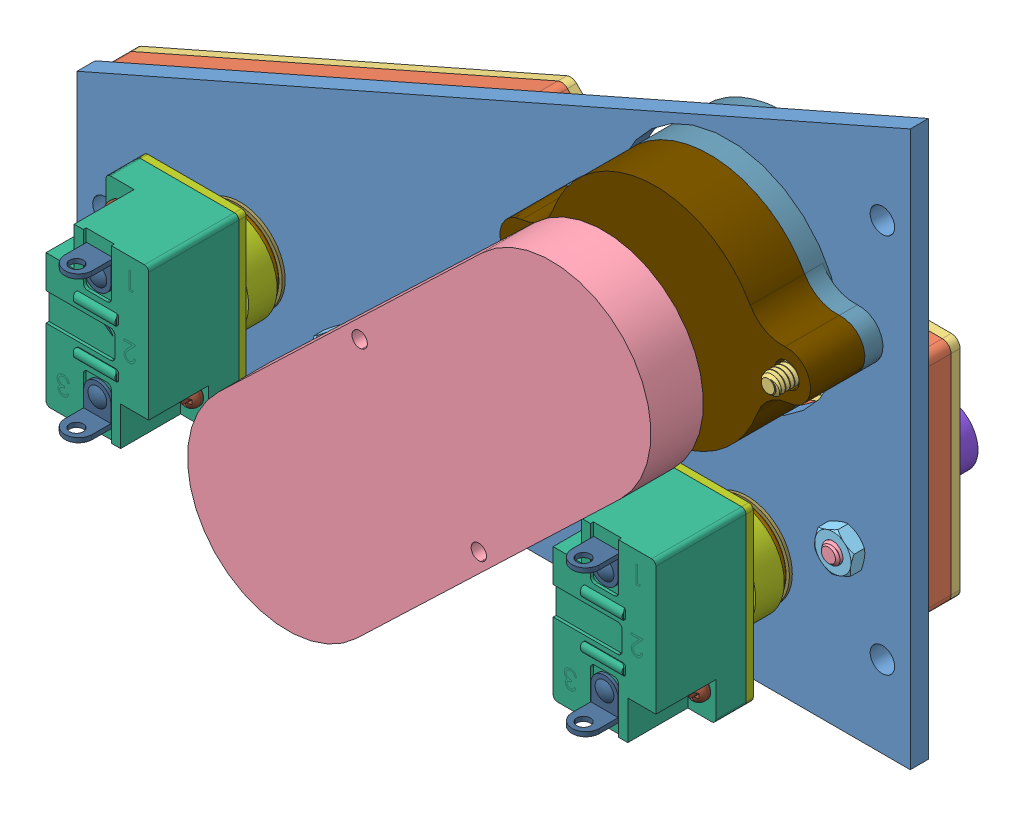
SolidWorks assembly ELEC Panel, configuration Default. Lengths in mm.
Overall size (184.74 131.22 81.65).
84 component instances, 31 part files, 35 mates.
Components (placement in the parent):
- ELEC Panel Backplate-1: ELEC Panel Backplate [Default] at origin size (146.05 97.28 3.4)
- ELEC Panel Lightplate-1: ELEC Panel Lightplate [Default] at (829.3636 5946.9 -37.6062) x (1 0 0) z (0 0 -1) size (144.46 65.08 4.76)
- ELEC Panel Legend Plate-1: ELEC Panel Legend Plate [Default] at (829.3636 5946.9 10.2422) x (1 0 0) z (0 0 -1) size (144.46 65.08 1.59)
- 91249A148 - PHS, 6-32 X .500, 18-8, BLACK-OXIDE-1: 91249A148 - PHS, 6-32 X .500, 18-8, BLACK-OXIDE [91249A148] at (-11.176 28.575 3.175) x (-0.851837 -0.523808 0) z (0 0 -1) size (6.86 6.86 15.21)
- 90760A007 - NUT, 6-32, JAM, STEEL, ZINC-PLATED-1: 90760A007 - NUT, 6-32, JAM, STEEL, ZINC-PLATED [90760A007] at (-11.176 28.575 1.1906) x (0.356702 -0.934218 0) z (-0.934218 -0.356702 0) size (6.35 2.99 7.33)
- 91249A148 - PHS, 6-32 X .500, 18-8, BLACK-OXIDE-2: 91249A148 - PHS, 6-32 X .500, 18-8, BLACK-OXIDE [91249A148] at (-60.325 46.0375 3.175) x (-0.75801 -0.652243 0) z (0 0 -1) size (6.86 6.86 15.21)
- 90760A007 - NUT, 6-32, JAM, STEEL, ZINC-PLATED-2: 90760A007 - NUT, 6-32, JAM, STEEL, ZINC-PLATED [90760A007] at (-60.325 46.0375 1.1906) x (0.500313 -0.865845 0) z (-0.865845 -0.500313 0) size (6.35 2.99 7.33)
- 91249A148 - PHS, 6-32 X .500, 18-8, BLACK-OXIDE-3: 91249A148 - PHS, 6-32 X .500, 18-8, BLACK-OXIDE [91249A148] at (-99.06 14.2875 3.175) x (-0.668789 -0.743453 0) z (0 0 -1) size (6.86 6.86 15.21)
- 90760A007 - NUT, 6-32, JAM, STEEL, ZINC-PLATED-3: 90760A007 - NUT, 6-32, JAM, STEEL, ZINC-PLATED [90760A007] at (-99.06 14.2875 1.1906) x (0.60649 -0.795091 0) z (-0.795091 -0.60649 0) size (6.35 2.99 7.33)
- SxAL-1: SxAL [S1AL - Conical Bat] at (-28.575 19.3759 9.2202) x (-1 0 0) z (0 -1 0) size (18.01 62.84 30)
  - S2AL_SMC_body1-body-1: S2AL_SMC_body1-body [Default] at origin size (18.01 16.36 30)
  - S2AL_SMC_plate13-1: S2AL_SMC_plate13 [Default] at origin size (18.01 21.39 30)
  - S2AL_S2AL_bat-1: S2AL_S2AL_bat [Removed Bat] at (0 14.7066 0) size (7.39 24.87 7.39)
  - S2AL_AT537-1: S2AL_AT537 [Default] at (0 7.9629 0) x (1 0 0) z (0 -1 0) size (15.49 15.49 1.5)
  - S2AL_SMC_trmnls2-terminals-1: S2AL_SMC_trmnls2-terminals [Default] at (0 -15.0114 0) size (16.2 6.6 44.08)
  - S2AL_M2_5x7_5-1: S2AL_M2_5x7_5 [Default] at (6.4643 -5.2832 -10.541) x (1 0 0) z (0 -1 0) size (3.56 3.56 9.47)
  - S2AL_M2_5x7_5-2: S2AL_M2_5x7_5 [Default] at (-6.4643 -5.2832 10.541) x (1 0 0) z (0 -1 0) size (3.56 3.56 9.47)
  - S2AL_AT508-1: S2AL_AT508 [Default] at (0 8.9662 0) x (1 0 0) z (0 -1 0) size (15.8 15.8 0.51)
  - S2AL_AT503M-1: S2AL_AT503M [Default] at (0 12.0396 0) x (1 0 0) z (0 1 0) size (16 14 2.4)
  - Tall Locking Bat-1: Tall Locking Bat [Default] at origin (suppressed, hidden)
  - Conical Locking Bat-1: Conical Locking Bat [Default] x (0 0 -1) z (1 0 0) size (11.18 15.95 11.18)
  - Round Locking Bat-1: Round Locking Bat [Default] x (0 0 -1) z (1 0 0) (suppressed, hidden)
- SxAL-2: SxAL [S1AL - Conical Bat] at (-117.475 19.558 9.2202) x (-1 0 0) z (0 -1 0) size (18.01 62.84 30)
  - S2AL_SMC_body1-body-1: S2AL_SMC_body1-body [Default] at origin size (18.01 16.36 30)
  - S2AL_SMC_plate13-1: S2AL_SMC_plate13 [Default] at origin size (18.01 21.39 30)
  - S2AL_S2AL_bat-1: S2AL_S2AL_bat [Removed Bat] at (0 14.7066 0) size (7.39 24.87 7.39)
  - S2AL_AT537-1: S2AL_AT537 [Default] at (0 7.9629 0) x (1 0 0) z (0 -1 0) size (15.49 15.49 1.5)
  - S2AL_SMC_trmnls2-terminals-1: S2AL_SMC_trmnls2-terminals [Default] at (0 -15.0114 0) size (16.2 6.6 44.08)
  - S2AL_M2_5x7_5-1: S2AL_M2_5x7_5 [Default] at (6.4643 -5.2832 -10.541) x (1 0 0) z (0 -1 0) size (3.56 3.56 9.47)
  - S2AL_M2_5x7_5-2: S2AL_M2_5x7_5 [Default] at (-6.4643 -5.2832 10.541) x (1 0 0) z (0 -1 0) size (3.56 3.56 9.47)
  - S2AL_AT508-1: S2AL_AT508 [Default] at (0 8.9662 0) x (1 0 0) z (0 -1 0) size (15.8 15.8 0.51)
  - S2AL_AT503M-1: S2AL_AT503M [Default] at (0 12.0396 0) x (1 0 0) z (0 1 0) size (16 14 2.4)
  - Tall Locking Bat-1: Tall Locking Bat [Default] at origin (suppressed, hidden)
  - Conical Locking Bat-1: Conical Locking Bat [Default] x (0 0 -1) z (1 0 0) size (11.18 15.95 11.18)
  - Round Locking Bat-1: Round Locking Bat [Default] x (0 0 -1) z (1 0 0) (suppressed, hidden)
- SxAL-3: SxAL [S3AL - Round Bat] at (-73.025 19.558 9.2202) x (-1 0 0) z (0 -1 0) size (18.01 65.15 30)
  - S2AL_SMC_body1-body-1: S2AL_SMC_body1-body [Default] at origin size (18.01 16.36 30)
  - S2AL_SMC_plate13-1: S2AL_SMC_plate13 [Default] at origin size (18.01 21.39 30)
  - S2AL_S2AL_bat-1: S2AL_S2AL_bat [Removed Bat] at (0 14.7066 0) size (7.39 24.87 7.39)
  - S2AL_AT537-1: S2AL_AT537 [Default] at (0 7.9629 0) x (1 0 0) z (0 -1 0) size (15.49 15.49 1.5)
  - S2AL_SMC_trmnls2-terminals-1: S2AL_SMC_trmnls2-terminals [Default] at (0 -15.0114 0) size (16.2 6.6 44.08)
  - S2AL_M2_5x7_5-1: S2AL_M2_5x7_5 [Default] at (6.4643 -5.2832 -10.541) x (1 0 0) z (0 -1 0) size (3.56 3.56 9.47)
  - S2AL_M2_5x7_5-2: S2AL_M2_5x7_5 [Default] at (-6.4643 -5.2832 10.541) x (1 0 0) z (0 -1 0) size (3.56 3.56 9.47)
  - S2AL_AT508-1: S2AL_AT508 [Default] at (0 8.9662 0) x (1 0 0) z (0 -1 0) size (15.8 15.8 0.51)
  - S2AL_AT503M-1: S2AL_AT503M [Default] at (0 12.0396 0) x (1 0 0) z (0 1 0) size (16 14 2.4)
  - Tall Locking Bat-1: Tall Locking Bat [Default] at origin (suppressed, hidden)
  - Conical Locking Bat-1: Conical Locking Bat [Default] x (0 0 -1) z (1 0 0) size (11.18 15.95 11.18) (suppressed, hidden)
  - Round Locking Bat-1: Round Locking Bat [Default] x (0 0 -1) z (1 0 0)
- Battery Voltage Indicator-1: Battery Voltage Indicator [Default] at (-32.004 59.944 -11.1125) x (0.996654 0.081731 0) z (0 0 -1) size (132.95 120.76 56.35)
  - 1.5 IN Case-1: 1.5 IN Case [Default] x (1 0 0) z (0 -1 0) size (54.61 14.29 38.1)
  - 1.5 Indicator Glass-1: 1.5 Indicator Glass [Default] at (0 0 -1.5875) x (-1 0 0) z (0 0 -1) size (32.84 32.84 1.59)
  - Battery Voltage Indicator Spacer-1: Battery Voltage Indicator Spacer [Default] at (0 0 -3.175) x (-1 0 0) z (0 0 -1) size (32.84 32.84 6.35)
  - Battery Voltage Indicator Bezel Face-1: Battery Voltage Indicator Bezel Face [Default] at (0 0 -11.1125) x (-1 0 0) z (0 0 1) size (32.84 32.84 1.59)
  - 1.5 Indicator Rear Bezel Spacer-1: 1.5 Indicator Rear Bezel Spacer [Default] at (0 0 -11.1125) x (1 0 0) z (0 0 -1) size (54.61 38.1 12.7)
  - Battery Voltage Servo Mount-1: Battery Voltage Servo Mount [Default] at (0 0 -23.8125) x (1 0 0) z (0 0 -1) size (24.55 36.67 18.54)
  - Battery Voltage Pointer-1: Battery Voltage Pointer [#1 Needle] at (0 0 -9.525) x (0.438476 0.898743 0) z (0 0 1) size (8.26 15.24 1.59)
  - spur gear_ai-2: spur gear_ai [PreviewCfg] at (0 0 -25.4) x (0 0 -1) z (0.923728 0.383049 0) size (12.7 86.43 86.43)
  - spur gear_ai-3: spur gear_ai [PreviewCfg] at (-7.7766 5.5 -38.1) x (0 0 1) z (-0.47771 -0.878518 0) size (12.7 86.43 86.43)
  - SERVO, SUB-NANO, 3.7G, GENERIC-2: SERVO, SUB-NANO, 3.7G, GENERIC [Default] at (-12.2766 -10 -56.35) size (9.5 32.5 24.6)
  - Battery Voltage Pointer-2: Battery Voltage Pointer [#2 Needle] at (0 0 -7.1437) x (0.44703 -0.894519 0) z (0 0 1) size (8.26 15.24 1.59)
  - spur gear_ai-4: spur gear_ai [PreviewCfg] at (0 0 -30.1625) x (0 0 -1) z (0.923728 0.383049 0) size (12.7 86.43 86.43)
  - spur gear_ai-5: spur gear_ai [PreviewCfg] at (7.7766 5.5 -33.3375) x (0 0 1) z (-0.486959 -0.873425 0) size (12.7 86.43 86.43)
  - SERVO, SUB-NANO, 3.7G, GENERIC-1: SERVO, SUB-NANO, 3.7G, GENERIC [Default] at (3.2766 -10 -56.35) size (9.5 32.5 24.6)
  - 93365A130_BRASS HEAT-SET INSERT FOR PLASTICS_6-32-3: 93365A130_BRASS HEAT-SET INSERT FOR PLASTICS_6-32 [93365A130] at (-23.1775 0 -14.2875) x (1 0 0) z (0 -1 0) size (5.56 4.29 5.56)
  - 93365A130_BRASS HEAT-SET INSERT FOR PLASTICS_6-32-4: 93365A130_BRASS HEAT-SET INSERT FOR PLASTICS_6-32 [93365A130] at (23.1775 0 -14.2875) x (0.987351 0.158553 0) z (0.158553 -0.987351 0) size (5.56 4.29 5.56)
  - 93365A102 - INSERT, 0-80, BRASS, FOR PLASTICS-1: 93365A102 - INSERT, 0-80, BRASS, FOR PLASTICS [Default] at (-7.7766 -13 -42.35) x (-0.989224 0.146409 0) z (-0.146409 -0.989224 0) size (3.58 3.01 3.58)
  - 91772A061_18-8 SS PAN HEAD PHILLIPS MACHINE SCREW_#0-80 X .2812-1: 91772A061_18-8 SS PAN HEAD PHILLIPS MACHINE SCREW_#0-80 X .2812 [91772A061] at (-7.7766 -13 -36.2063) x (-0.460399 -0.887712 0) z (0 0 -1) size (2.95 2.95 8.26)
  - 93365A102 - INSERT, 0-80, BRASS, FOR PLASTICS-2: 93365A102 - INSERT, 0-80, BRASS, FOR PLASTICS [Default] at (-7.7766 13 -42.35) x (-0.989224 0.146409 0) z (-0.146409 -0.989224 0) size (3.58 3.01 3.58)
  - 93365A102 - INSERT, 0-80, BRASS, FOR PLASTICS-3: 93365A102 - INSERT, 0-80, BRASS, FOR PLASTICS [Default] at (7.7766 13 -42.35) x (-0.989224 0.146409 0) z (-0.146409 -0.989224 0) size (3.58 3.01 3.58)
  - 93365A102 - INSERT, 0-80, BRASS, FOR PLASTICS-4: 93365A102 - INSERT, 0-80, BRASS, FOR PLASTICS [Default] at (7.7766 -13 -42.35) x (-0.989224 0.146409 0) z (-0.146409 -0.989224 0) size (3.58 3.01 3.58)
  - 93365A102 - INSERT, 0-80, BRASS, FOR PLASTICS-5: 93365A102 - INSERT, 0-80, BRASS, FOR PLASTICS [Default] at (7.435 -14.69 -23.8125) x (0.989224 0.146409 0) z (0.146409 -0.989224 0) size (3.58 3.01 3.58)
  - 93365A102 - INSERT, 0-80, BRASS, FOR PLASTICS-6: 93365A102 - INSERT, 0-80, BRASS, FOR PLASTICS [Default] at (-7.7474 -14.6946 -23.8125) x (0.989224 0.146409 0) z (0.146409 -0.989224 0) size (3.58 3.01 3.58)
  - 93365A102 - INSERT, 0-80, BRASS, FOR PLASTICS-7: 93365A102 - INSERT, 0-80, BRASS, FOR PLASTICS [Default] at (7.435 14.69 -23.8125) x (0.989224 0.146409 0) z (0.146409 -0.989224 0) size (3.58 3.01 3.58)
  - 93365A102 - INSERT, 0-80, BRASS, FOR PLASTICS-8: 93365A102 - INSERT, 0-80, BRASS, FOR PLASTICS [Default] at (-7.7474 14.6946 -23.8125) x (0.989224 0.146409 0) z (0.146409 -0.989224 0) size (3.58 3.01 3.58)
  - 91772A061_18-8 SS PAN HEAD PHILLIPS MACHINE SCREW_#0-80 X .2812-2: 91772A061_18-8 SS PAN HEAD PHILLIPS MACHINE SCREW_#0-80 X .2812 [91772A061] at (-7.7766 13 -36.2063) x (-0.460399 -0.887712 0) z (0 0 -1) size (2.95 2.95 8.26)
  - 91772A061_18-8 SS PAN HEAD PHILLIPS MACHINE SCREW_#0-80 X .2812-3: 91772A061_18-8 SS PAN HEAD PHILLIPS MACHINE SCREW_#0-80 X .2812 [91772A061] at (7.7766 13 -36.2063) x (-0.460399 -0.887712 0) z (0 0 -1) size (2.95 2.95 8.26)
  - 91772A061_18-8 SS PAN HEAD PHILLIPS MACHINE SCREW_#0-80 X .2812-4: 91772A061_18-8 SS PAN HEAD PHILLIPS MACHINE SCREW_#0-80 X .2812 [91772A061] at (7.7766 -13 -36.2063) x (-0.460399 -0.887712 0) z (0 0 -1) size (2.95 2.95 8.26)
  - 91772A064 - PHS, 0-80 x .4375, 18-8-1: 91772A064 - PHS, 0-80 x .4375, 18-8 [91772A064] at (7.435 -14.69 -28.575) x (-0.800587 -0.599216 0) z (0 0 1) size (2.95 2.95 12.24)
  - 91772A064 - PHS, 0-80 x .4375, 18-8-2: 91772A064 - PHS, 0-80 x .4375, 18-8 [91772A064] at (-7.7474 -14.6946 -28.575) x (-0.800587 -0.599216 0) z (0 0 1) size (2.95 2.95 12.24)
  - 91772A064 - PHS, 0-80 x .4375, 18-8-3: 91772A064 - PHS, 0-80 x .4375, 18-8 [91772A064] at (7.435 14.69 -28.575) x (-0.800587 -0.599216 0) z (0 0 1) size (2.95 2.95 12.24)
  - 91772A064 - PHS, 0-80 x .4375, 18-8-4: 91772A064 - PHS, 0-80 x .4375, 18-8 [91772A064] at (-7.7474 14.6946 -28.575) x (-0.800587 -0.599216 0) z (0 0 1) size (2.95 2.95 12.24)
- 90471A223 - FHS, 100DEG, 6-32 x .750, STEEL, ZINC-1: 90471A223 - FHS, 100DEG, 6-32 x .750, STEEL, ZINC [90471A223] at (-8.904 61.8383 -1.4698) x (0.785309 -0.619104 0) z (0 0 -1) size (6.65 6.65 19.4)
- 90471A223 - FHS, 100DEG, 6-32 x .750, STEEL, ZINC-2: 90471A223 - FHS, 100DEG, 6-32 x .750, STEEL, ZINC [90471A223] at (-55.104 58.0497 -1.4698) x (0.873536 -0.486759 0) z (0 0 -1) size (6.65 6.65 19.4)
- VID28-05-1: VID28-05 [Default] at (-38.8665 53.3747 38.0055) x (0.72237 0.691507 0) z (-0.691507 0.72237 0) size (99 26.6 35)
Mates (geometry in assembly coordinates):
- Concentric37: concentric aligned: circle of ELEC Panel Backplate-1; cylinder of ELEC Panel Lightplate-1 through (-117.475 19.558 -3.175) axis (0 0 -1) radius 9.525
- Concentric38: concentric aligned: cylinder of ELEC Panel Backplate-1 through (-73.025 19.558 0) axis (0 0 -1) radius 6.35; cylinder of ELEC Panel Lightplate-1 through (-73.025 19.558 -3.175) axis (0 0 -1) radius 9.525
- Coincident68: coincident anti-aligned: plane of ELEC Panel Backplate-1 through (0 0 -3.175) normal (0 0 -1); plane of ELEC Panel Lightplate-1 through (-12.7635 2.3177 -3.175) normal (0 0 1)
- Coincident69: coincident aligned: plane of ELEC Panel Lightplate-1 through (-145.2562 22.1615 -7.9375) normal (-1 0 0); plane of ELEC Panel Legend Plate-1 through (-145.2562 22.1615 -9.525) normal (-1 0 0)
- Coincident70: coincident aligned: plane of ELEC Panel Lightplate-1 through (-144.346 32.9026 -7.9375) normal (-0.402739 0.915315 0); plane of ELEC Panel Legend Plate-1 through (-144.346 32.9026 -9.525) normal (-0.402739 0.915315 0)
- Coincident71: coincident anti-aligned: plane of ELEC Panel Lightplate-1 through (-12.7635 2.3177 -7.9375) normal (0 0 -1); plane of ELEC Panel Legend Plate-1 through (-12.7635 2.3177 -7.9375) normal (0 0 1)
- Concentric39: concentric anti-aligned: cylinder of ELEC Panel Legend Plate-1 through (-11.176 28.575 -9.525) axis (0 0 -1) radius 2.1526; cylinder of 91249A148 - PHS, 6-32 X .500, 18-8, BLACK-OXIDE-1 through (-11.176 28.575 3.175) axis (0 0 1) radius 3.429
- Coincident72: coincident anti-aligned: plane of ELEC Panel Legend Plate-1 through (-12.7635 2.3177 -9.525) normal (0 0 -1); plane of 91249A148 - PHS, 6-32 X .500, 18-8, BLACK-OXIDE-1 through (-11.176 28.575 -9.525) normal (0 0 1)
- Concentric40: concentric anti-aligned: cylinder of 91249A148 - PHS, 6-32 X .500, 18-8, BLACK-OXIDE-1 through (-11.176 28.575 3.175) axis (0 0 1) radius 3.429; circle of 90760A007 - NUT, 6-32, JAM, STEEL, ZINC-PLATED-1
- Coincident73: coincident anti-aligned: plane of ELEC Panel Backplate-1 through (0 0 0) normal (0 0 1); plane of 90760A007 - NUT, 6-32, JAM, STEEL, ZINC-PLATED-1 through (-10.596 32.195 0) normal (0 0 -1)
- Concentric41: concentric anti-aligned: cylinder of 91249A148 - PHS, 6-32 X .500, 18-8, BLACK-OXIDE-2 through (-60.325 46.0375 3.175) axis (0 0 1) radius 3.429; circle of 90760A007 - NUT, 6-32, JAM, STEEL, ZINC-PLATED-2
- Coincident74: coincident anti-aligned: plane of ELEC Panel Legend Plate-1 through (-12.7635 2.3177 -9.525) normal (0 0 -1); plane of 91249A148 - PHS, 6-32 X .500, 18-8, BLACK-OXIDE-2 through (-60.325 46.0375 -9.525) normal (0 0 1)
- Coincident75: coincident anti-aligned: plane of ELEC Panel Backplate-1 through (0 0 0) normal (0 0 1); plane of 90760A007 - NUT, 6-32, JAM, STEEL, ZINC-PLATED-2 through (-60.3263 49.7037 0) normal (0 0 -1)
- Concentric42: concentric anti-aligned: cylinder of ELEC Panel Legend Plate-1 through (-60.325 46.0375 -9.525) axis (0 0 -1) radius 2.1526; cylinder of 91249A148 - PHS, 6-32 X .500, 18-8, BLACK-OXIDE-2 through (-60.325 46.0375 3.175) axis (0 0 1) radius 3.429
- Concentric43: concentric anti-aligned: cylinder of 91249A148 - PHS, 6-32 X .500, 18-8, BLACK-OXIDE-3 through (-99.06 14.2875 3.175) axis (0 0 1) radius 3.429; circle of 90760A007 - NUT, 6-32, JAM, STEEL, ZINC-PLATED-3
- Coincident76: coincident anti-aligned: plane of ELEC Panel Legend Plate-1 through (-12.7635 2.3177 -9.525) normal (0 0 -1); plane of 91249A148 - PHS, 6-32 X .500, 18-8, BLACK-OXIDE-3 through (-99.06 14.2875 -9.525) normal (0 0 1)
- Coincident77: coincident anti-aligned: plane of ELEC Panel Backplate-1 through (0 0 0) normal (0 0 1); plane of 90760A007 - NUT, 6-32, JAM, STEEL, ZINC-PLATED-3 through (-99.5281 17.9237 0) normal (0 0 -1)
- Concentric44: concentric anti-aligned: cylinder of ELEC Panel Legend Plate-1 through (-99.06 14.2875 -9.525) axis (0 0 -1) radius 2.1526; cylinder of 91249A148 - PHS, 6-32 X .500, 18-8, BLACK-OXIDE-3 through (-99.06 14.2875 3.175) axis (0 0 1) radius 3.429
- Concentric45: concentric aligned: cylinder of ELEC Panel Backplate-1 through (-28.575 19.3759 0) axis (0 0 -1) radius 6.35; cylinder of SxAL-1/S2AL_SMC_plate13-1 through (-28.575 19.3759 8.2804) axis (0 0 -1) radius 6
- Parallel1: parallel aligned: plane of ELEC Panel Backplate-1 through (0 0 -3.175) normal (1 0 0); plane of SxAL-1/S2AL_SMC_body1-body-1 through (-19.5707 33.6126 25.019) normal (1 0 0)
- Coincident78: coincident anti-aligned: plane of ELEC Panel Backplate-1 through (0 0 0) normal (0 0 1); plane of SxAL-1/S2AL_AT508-1 through (-28.575 19.3759 0) normal (0 0 -1)
- Parallel2: parallel aligned: plane of ELEC Panel Backplate-1 through (0 0 -3.175) normal (1 0 0); plane of SxAL-2/S2AL_SMC_body1-body-1 through (-108.4707 33.7947 25.019) normal (1 0 0)
- Coincident79: coincident anti-aligned: plane of ELEC Panel Backplate-1 through (0 0 0) normal (0 0 1); plane of SxAL-2/S2AL_AT508-1 through (-117.475 19.558 0) normal (0 0 -1)
- Concentric46: concentric aligned: cylinder of ELEC Panel Backplate-1 through (-117.475 19.558 0) axis (0 0 -1) radius 6.35; cylinder of SxAL-2/S2AL_SMC_plate13-1 through (-117.475 19.558 8.2804) axis (0 0 -1) radius 6
- Coincident80: coincident anti-aligned: plane of ELEC Panel Backplate-1 through (0 0 0) normal (0 0 1); plane of SxAL-3/S2AL_AT508-1 through (-73.025 19.558 0) normal (0 0 -1)
- Parallel3: parallel aligned: plane of ELEC Panel Backplate-1 through (0 0 -3.175) normal (1 0 0); plane of SxAL-3/S2AL_SMC_body1-body-1 through (-64.0207 33.7947 25.019) normal (1 0 0)
- Concentric47: concentric aligned: cylinder of ELEC Panel Backplate-1 through (-73.025 19.558 0) axis (0 0 -1) radius 6.35; cylinder of SxAL-3/S2AL_SMC_plate13-1 through (-73.025 19.558 8.2804) axis (0 0 -1) radius 6
- Concentric48: concentric: cylinder of Battery Voltage Indicator-1/1.5 IN Case-1 through (-32.004 59.944 -9.525) axis (0 0 -1) radius 19.05; cylinder of ELEC Panel Backplate-1 through (-32.004 59.944 0) axis (0 0 -1) radius 19.8438
- Concentric49: concentric aligned: cone of ELEC Panel Backplate-1 through (-8.904 61.8383 -3.175) axis (0 0 1); cone of 90471A223 - FHS, 100DEG, 6-32 x .750, STEEL, ZINC-1 through (-8.904 61.8383 -2.9938) axis (0 0 1)
- Coincident81: coincident aligned: cone of ELEC Panel Backplate-1 through (-8.904 61.8383 -3.175) axis (0 0 1); cone of 90471A223 - FHS, 100DEG, 6-32 x .750, STEEL, ZINC-1 through (-8.904 61.8383 -2.9938) axis (0 0 1)
- Concentric50: concentric aligned: cone of ELEC Panel Backplate-1 through (-55.104 58.0497 -3.175) axis (0 0 1); cone of 90471A223 - FHS, 100DEG, 6-32 x .750, STEEL, ZINC-2 through (-55.104 58.0497 -2.9938) axis (0 0 1)
- Coincident82: coincident aligned: cone of ELEC Panel Backplate-1 through (-55.104 58.0497 -3.175) axis (0 0 1); cone of 90471A223 - FHS, 100DEG, 6-32 x .750, STEEL, ZINC-2 through (-55.104 58.0497 -2.9938) axis (0 0 1)
- Concentric51: concentric anti-aligned: cone of Battery Voltage Indicator-1/Needle #2 Concentric Needle Shaft-1 through (-32.004 59.944 30.6055) axis (0 0 -1); cylinder of VID28-05-1 through (-32.004 59.944 38.0055) axis (0 0 1) radius 2
- Distance1: distance = 1 mm anti-aligned: plane of VID28-05-1 through (-30.2752 58.1381 31.6055) normal (0 0 -1); plane of Battery Voltage Indicator-1/Needle #2 Concentric Needle Shaft-1 through (-32.004 59.944 30.6055) normal (0 0 1)
- Angle1: planar angle = 0.349066 rad aligned: plane of VID28-05-1 through (-74.0837 43.8879 47.2055) normal (-0.691507 0.72237 0); plane of ELEC Panel Backplate-1 through (0 97.282 -3.175) normal (-0.402739 0.915315 0)
